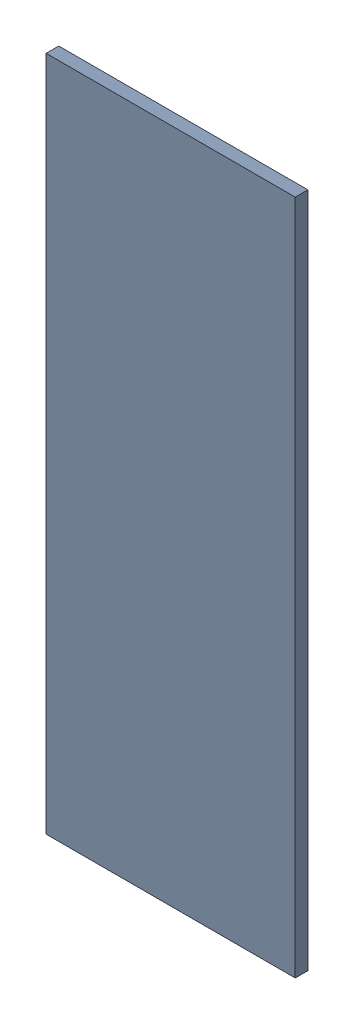
SolidWorks assembly Pad RAK4600-35(26.225mm,31.391mm) on Top Layer, configuration Predeterminado. Lengths in mm.
Overall size (0.7 1.9 0.04).
2 component instances, 1 part files, 0 mates.
Components (placement in the parent):
- Pad RAK4600-35(26.225mm,31.391mm) on Top Layer-1-1: Pad RAK4600-35(26.225mm,31.391mm) on Top Layer-1 [Predeterminado] at (-68.317 -44.187 -0.0457) size (0.7 1.9 0.04)
  - Pad RAK4600-35(26.225mm,31.391mm) on Top Layer-Part-1-1: Pad RAK4600-35(26.225mm,31.391mm) on Top Layer-Part-1 [Predeterminado] at origin size (0.7 1.9 0.04)
